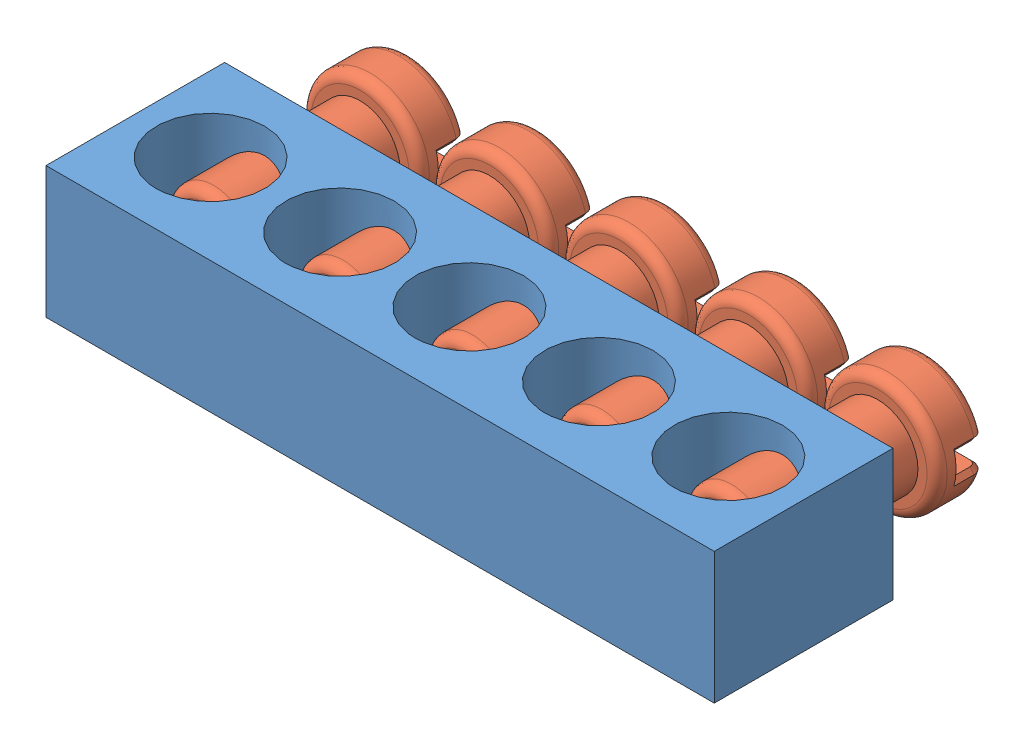
SolidWorks assembly bus-bar, configuration Default. Lengths in mm.
Overall size (33.3 6.55 14.35).
6 component instances, 2 part files, 19 mates.
Components (placement in the parent):
- bus-bar-body-1: bus-bar-body [Default] at origin size (33.3 6.55 8.9)
- bus-bar-screw-1: bus-bar-screw [Default] at (-12.9 3.275 0.35) x (0 1 0) z (-1 0 0) size (5.9 10.25 5.9)
- bus-bar-screw-2: bus-bar-screw [Default] at (-6.45 3.275 0.35) x (0 1 0) z (-1 0 0) size (5.9 10.25 5.9)
- bus-bar-screw-3: bus-bar-screw [Default] at (0 3.275 0.35) x (0 1 0) z (-1 0 0) size (5.9 10.25 5.9)
- bus-bar-screw-4: bus-bar-screw [Default] at (6.45 3.275 0.35) x (0 1 0) z (-1 0 0) size (5.9 10.25 5.9)
- bus-bar-screw-5: bus-bar-screw [Default] at (12.9 3.275 0.35) x (0 1 0) z (-1 0 0) size (5.9 10.25 5.9)
Mates (geometry in assembly coordinates):
- Concentric1: concentric anti-aligned: cylinder of bus-bar-body-1 through (-12.9 3.275 4.451) axis (0 0 -1) radius 2; cylinder of bus-bar-screw-1 through (-12.9 3.275 -7.45) axis (0 0 1) radius 2
- Distance1: distance = 3 mm anti-aligned: plane of bus-bar-screw-1 through (-12.9 3.275 -7.45) normal (0 0 1); plane of bus-bar-body-1 through (-16.65 6.55 -4.45) normal (0 0 -1)
- Parallel1: parallel aligned: plane of bus-bar-body-1 through (0 6.55 0) normal (0 1 0); plane of bus-bar-screw-1 through (-15.85 2.725 -8.4) normal (0 1 0)
- Concentric2: concentric anti-aligned: cylinder of bus-bar-body-1 through (-6.45 3.275 4.451) axis (0 0 -1) radius 2; cylinder of bus-bar-screw-2 through (-6.45 3.275 -7.45) axis (0 0 1) radius 2
- Distance2: distance = 3 mm anti-aligned: plane of bus-bar-screw-2 through (-6.45 3.275 -7.45) normal (0 0 1); plane of bus-bar-body-1 through (-16.65 6.55 -4.45) normal (0 0 -1)
- Parallel2: parallel aligned: plane of bus-bar-body-1 through (0 6.55 0) normal (0 1 0); plane of bus-bar-screw-2 through (-9.4 2.725 -8.4) normal (0 1 0)
- Distance3: distance = 3 mm anti-aligned: plane of bus-bar-screw-3 through (0 3.275 -7.45) normal (0 0 1); plane of bus-bar-body-1 through (-16.65 6.55 -4.45) normal (0 0 -1)
- Parallel3: parallel aligned: plane of bus-bar-body-1 through (0 6.55 0) normal (0 1 0); plane of bus-bar-screw-3 through (-2.95 2.725 -8.4) normal (0 1 0)
- Concentric3: concentric anti-aligned: cylinder of bus-bar-body-1 through (0 3.275 4.451) axis (0 0 -1) radius 2; cylinder of bus-bar-screw-3 through (0 3.275 -7.45) axis (0 0 1) radius 2
- Distance4: distance = 3 mm anti-aligned: plane of bus-bar-screw-4 through (6.45 3.275 -7.45) normal (0 0 1); plane of bus-bar-body-1 through (-16.65 6.55 -4.45) normal (0 0 -1)
- Parallel4: parallel aligned: plane of bus-bar-body-1 through (0 6.55 0) normal (0 1 0); plane of bus-bar-screw-4 through (3.5 2.725 -8.4) normal (0 1 0)
- Concentric4: concentric anti-aligned: cylinder of bus-bar-body-1 through (6.45 3.275 4.451) axis (0 0 -1) radius 2; cylinder of bus-bar-screw-4 through (6.45 3.275 -7.45) axis (0 0 1) radius 2
- Distance5: distance = 3 mm anti-aligned: plane of bus-bar-screw-5 through (12.9 3.275 -7.45) normal (0 0 1); plane of bus-bar-body-1 through (-16.65 6.55 -4.45) normal (0 0 -1)
- Parallel5: parallel aligned: plane of bus-bar-body-1 through (0 6.55 0) normal (0 1 0); plane of bus-bar-screw-5 through (9.95 2.725 -8.4) normal (0 1 0)
- Concentric5: concentric anti-aligned: cylinder of bus-bar-body-1 through (12.9 3.275 4.451) axis (0 0 -1) radius 2; cylinder of bus-bar-screw-5 through (12.9 3.275 -7.45) axis (0 0 1) radius 2
- InPlace1: in place: plane of bus-bar-body-1 through (-16.65 6.55 -4.45) normal (-1 0 0); plane of ? through (-16.65 0 0) normal (-1 0 0); moOrthogonalPlaneRef_w of bus-bar-body-1 through (-16.65 6.55 -4.45) normal (-1 0 0); plane of ? through (-16.65 0 0) normal (0 1 0); plane of bus-bar-body-1 through (-16.65 6.55 -4.45) normal (-1 0 0); plane of ? through (-16.65 0 0) normal (0 0 1); plane of bus-bar-body-1 through (-16.65 6.55 -4.45) normal (-1 0 0); unknown of ?
- Coincident3: coincident aligned: plane of bus-bar-body-1; plane of ?
- Coincident4: coincident aligned: moOrthogonalPlaneRef_w of bus-bar-body-1 through (-16.65 0 0) normal (0 1 0); plane of Part13^bus-bar-1 through (-16.65 0 0) normal (0 1 0)
- Coincident5: coincident anti-aligned: moOrthogonalPlaneRef_w of bus-bar-body-1 through (-16.65 0 0) normal (0 0 -1); plane of Part13^bus-bar-1 through (-16.65 0 0) normal (0 0 1)
